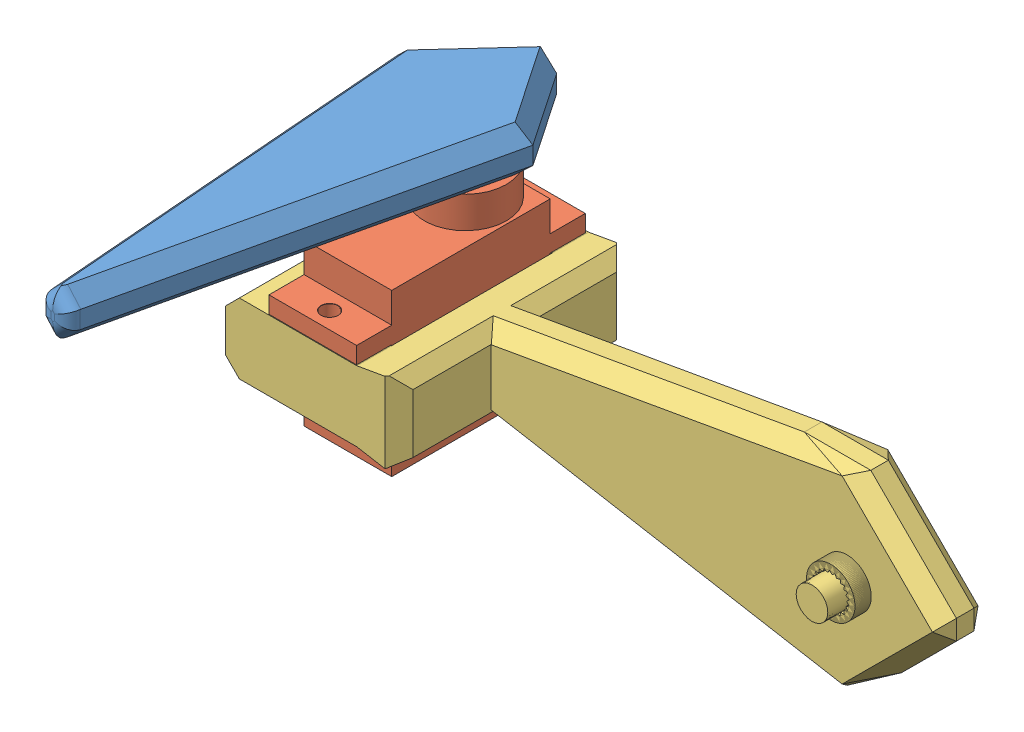
SolidWorks assembly right_legs_assembly, configuration Default. Lengths in mm.
Overall size (91.06 40.35 66.78).
3 component instances, 3 part files, 5 mates.
Components (placement in the parent):
- link_2_for_assembly-1: link_2_for_assembly [Default] at (152.7649 84.4555 188.6568) x (-0.07256 0 0.997364) z (0 -1 0) size (65 20.81 9.5)
- sg90_model-1: sg90_model [Default] at (149.0077 52.4555 197.3418) x (0 0 1) z (-1 0 0) size (32.6 27.5 12.5)
- right_side_link_1_for_assembly-1: right_side_link_1_for_assembly [Default] at (215.6213 67.256 199.0918) x (-1 0 0) z (0 0 1) size (89.08 28.24 33.02)
Mates (geometry in assembly coordinates):
- Concentric4: concentric anti-aligned: circle of link_2_for_assembly-1; circle of sg90_model-1
- Coincident2: coincident anti-aligned: plane of link_2_for_assembly-1 through (149.0077 79.9555 191.8918) normal (0 -1 0); plane of sg90_model-1 through (149.0077 79.9555 191.8918) normal (0 1 0)
- Concentric5: concentric aligned: circle of sg90_model-1; circle of right_side_link_1_for_assembly-1
- Concentric6: concentric aligned: circle of sg90_model-1; circle of right_side_link_1_for_assembly-1
- Coincident3: coincident anti-aligned: plane of sg90_model-1 through (149.0077 68.7555 197.3418) normal (0 -1 0); plane of right_side_link_1_for_assembly-1 through (215.6213 30.5894 199.0918) normal (0 1 0)
